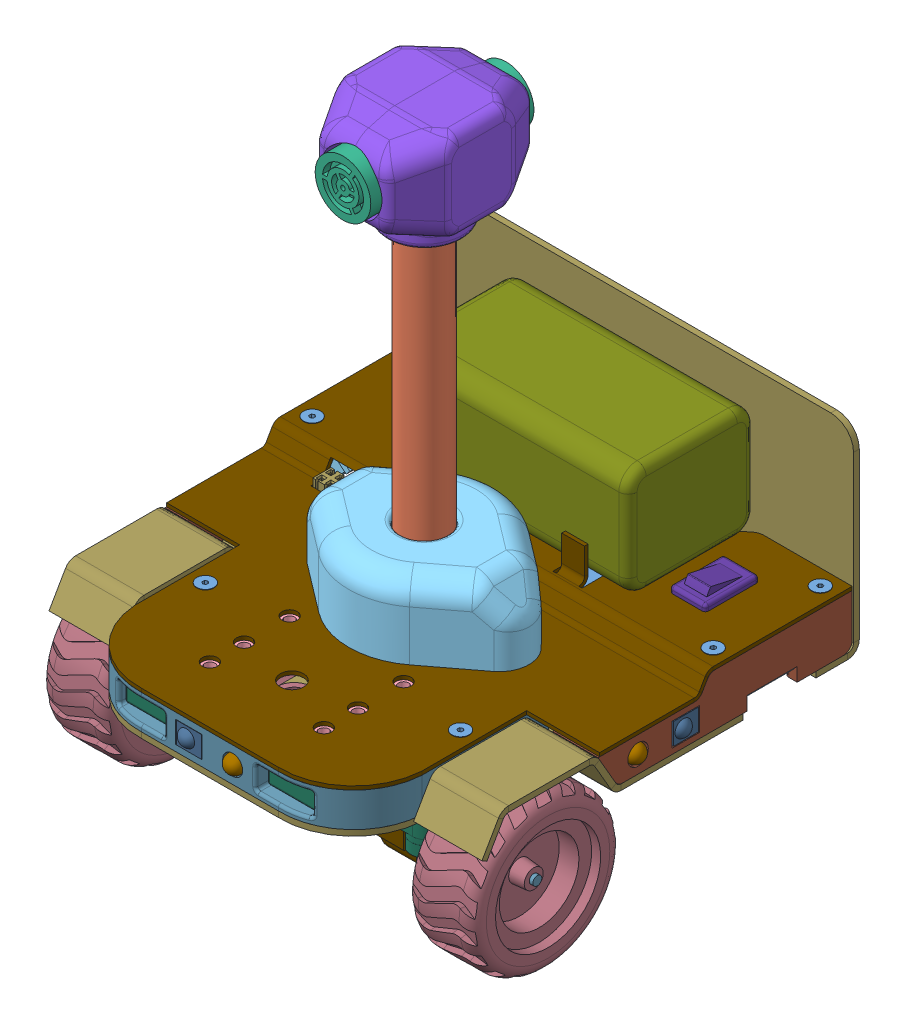
SolidWorks assembly SCOUT REAR, TOP ASSY, configuration Default. Lengths in mm.
Overall size (123.75 170.86 128.74).
86 component instances, 37 part files, 147 mates.
Components (placement in the parent):
- Socket Countersunk Head Cap Screw_AI-18: Socket Countersunk Head Cap Screw_AI [SCHCSCREW 0.086-56x0.3125x0.3125-HX-N] at (-15.9502 58.0469 -46.644) x (0 0 -1) z (1 0 0) size (7.94 4.79 4.79)
- Machine Screw Nut Hex_AI-2: Machine Screw Nut Hex_AI [MSHXNUT 0.086-56-D-N] at (-15.9502 58.0469 -52.9051) size (4.78 5.51 1.68)
- Socket Countersunk Head Cap Screw_AI-1: Socket Countersunk Head Cap Screw_AI [SCHCSCREW 0.086-56x0.188x0.188-HX-N] at (-26.2031 27.9504 40.5909) x (0 1 0) z (0 0 1) size (4.78 4.79 4.79)
- Socket Countersunk Head Cap Screw_AI-2: Socket Countersunk Head Cap Screw_AI [SCHCSCREW 0.086-56x0.188x0.188-HX-N] at (-50.3862 27.9504 -42.0212) x (0 1 0) z (0 0 1) size (4.78 4.79 4.79)
- Socket Countersunk Head Cap Screw_AI-3: Socket Countersunk Head Cap Screw_AI [SCHCSCREW 0.086-56x0.188x0.188-HX-N] at (-63.1312 27.9504 12.5888) x (0 1 0) z (0 0 1) size (4.78 4.79 4.79)
- Socket Countersunk Head Cap Screw_AI-4: Socket Countersunk Head Cap Screw_AI [SCHCSCREW 0.086-56x0.188x0.188-HX-N] at (-33.8762 27.9504 -26.7812) x (0 1 0) z (0 0 1) size (4.78 4.79 4.79)
- Socket Countersunk Head Cap Screw_AI-5: Socket Countersunk Head Cap Screw_AI [SCHCSCREW 0.086-56x0.188x0.188-HX-N] at (-33.8762 27.9504 -42.0212) x (0 1 0) z (0 0 1) size (4.78 4.79 4.79)
- Socket Countersunk Head Cap Screw_AI-6: Socket Countersunk Head Cap Screw_AI [SCHCSCREW 0.086-56x0.188x0.188-HX-N] at (-50.3862 27.9504 -26.7812) x (0 1 0) z (0 0 1) size (4.78 4.79 4.79)
- Socket Countersunk Head Cap Screw_AI-7: Socket Countersunk Head Cap Screw_AI [SCHCSCREW 0.086-56x0.188x0.188-HX-N] at (-21.1312 27.9504 12.5888) x (0 1 0) z (0 0 1) size (4.78 4.79 4.79)
- Socket Countersunk Head Cap Screw_AI-8: Socket Countersunk Head Cap Screw_AI [SCHCSCREW 0.086-56x0.188x0.188-HX-N] at (-26.2031 27.9504 51.7034) x (0 1 0) z (0 0 1) size (4.78 4.79 4.79)
- Socket Countersunk Head Cap Screw_AI-9: Socket Countersunk Head Cap Screw_AI [SCHCSCREW 0.086-56x0.188x0.188-HX-N] at (-58.0593 27.9504 51.7034) x (0 1 0) z (0 0 1) size (4.78 4.79 4.79)
- Socket Countersunk Head Cap Screw_AI-10: Socket Countersunk Head Cap Screw_AI [SCHCSCREW 0.086-56x0.188x0.188-HX-N] at (-58.0593 27.9504 40.5909) x (0 1 0) z (0 0 1) size (4.78 4.79 4.79)
- Socket Countersunk Head Cap Screw_AI-11: Socket Countersunk Head Cap Screw_AI [SCHCSCREW 0.086-56x0.188x0.188-HX-N] at (-75.9169 27.9504 58.6263) x (0 1 0) z (0 0 1) size (4.78 4.79 4.79)
- Socket Countersunk Head Cap Screw_AI-12: Socket Countersunk Head Cap Screw_AI [SCHCSCREW 0.086-56x0.188x0.188-HX-N] at (-8.3456 27.9504 58.6263) x (0 1 0) z (0 0 1) size (4.78 4.79 4.79)
- Socket Countersunk Head Cap Screw_AI-14: Socket Countersunk Head Cap Screw_AI [SCHCSCREW 0.086-56x0.188x0.188-HX-N] at (13.4313 27.9504 6.8738) x (0 1 0) z (0 0 1) size (4.78 4.79 4.79)
- Socket Countersunk Head Cap Screw_AI-15: Socket Countersunk Head Cap Screw_AI [SCHCSCREW 0.086-56x0.188x0.188-HX-N] at (-97.6937 27.9504 6.8738) x (0 1 0) z (0 0 1) size (4.78 4.79 4.79)
- Socket Countersunk Head Cap Screw_AI-16: Socket Countersunk Head Cap Screw_AI [SCHCSCREW 0.086-56x0.188x0.188-HX-N] at (-29.3042 27.9504 -16.291) x (0 1 0) z (0 0 1) size (4.78 4.79 4.79)
- Socket Countersunk Head Cap Screw_AI-17: Socket Countersunk Head Cap Screw_AI [SCHCSCREW 0.086-56x0.188x0.188-HX-N] at (-59.2762 27.9504 -6.766) x (0 1 0) z (0 0 1) size (4.78 4.79 4.79)
- Flat Head 100 Screw_AI-10: Flat Head 100 Screw_AI [CR-FHM1 0.112-40x0.25x0.25-N] at (-63.1312 46.6776 12.5888) x (0 -1 0) z (0 0 1) size (6.35 4.85 4.85)
- Flat Head 100 Screw_AI-11: Flat Head 100 Screw_AI [CR-FHM1 0.112-40x0.25x0.25-N] at (-21.1312 46.6776 12.5888) x (0 -1 0) z (0 0 1) size (6.35 4.85 4.85)
- Socket Head Cap Screw_AI-17: Socket Head Cap Screw_AI [HX-SHCS 0.086-56x0.4375x0.4375-N] at (-77.6912 31.862 47.5138) x (0 -1 0) z (-0.381305 0 -0.924449) size (13.3 3.56 3.56)
- Socket Head Cap Screw_AI-18: Socket Head Cap Screw_AI [HX-SHCS 0.086-56x0.4375x0.4375-N] at (-77.6912 31.862 29.5138) x (0 -1 0) z (0 0 1) size (13.3 3.56 3.56)
- Socket Head Cap Screw_AI-19: Socket Head Cap Screw_AI [HX-SHCS 0.086-56x0.4375x0.4375-N] at (-6.5712 31.862 29.5138) x (0 -1 0) z (0 0 1) size (13.3 3.56 3.56)
- Socket Head Cap Screw_AI-20: Socket Head Cap Screw_AI [HX-SHCS 0.086-56x0.4375x0.4375-N] at (-6.5712 31.862 47.5138) x (0 -1 0) z (0 0 1) size (13.3 3.56 3.56)
- SENSOR, CLIFF, GP2Y0D810-1: SENSOR, CLIFF, GP2Y0D810 [Default] at (9.9271 36.5946 -23.9419) x (0 0 -1) z (0.766044 0.642788 0) size (21.46 9.46 8.89)
- SENSOR, CLIFF, GP2Y0D810-2: SENSOR, CLIFF, GP2Y0D810 [Default] at (-94.1896 36.5946 -23.9419) x (0 0 -1) z (0.766044 -0.642788 0) size (21.46 9.46 8.89)
- SENSOR, SONAR, Maxbotix EZ4-1: SENSOR, SONAR, Maxbotix EZ4 [Default] at (-42.0042 152.0321 6.2388) x (0 1 0) z (0 0 -1) size (19.94 22.1 16.38)
- SENSOR, SONAR, Maxbotix EZ4-2: SENSOR, SONAR, Maxbotix EZ4 [Default] at (-42.0042 152.0321 18.9388) x (0 -1 0) z (0 0 1) size (19.94 22.1 16.38)
- SENSOR, SONAR, MOUNTING BLOCK-1: SENSOR, SONAR, MOUNTING BLOCK [Default] at (-42.1312 151.9686 12.5888) x (-1 0 0) z (0 0 -1) size (22.35 20.07 12.7)
- SENSOR, SONAR, COVER-1: SENSOR, SONAR, COVER [Default] at (-42.0042 152.0321 12.5888) size (15.88 31.75 40.64)
- SENSOR, SONAR, COVER-2: SENSOR, SONAR, COVER [Default] at (-42.0042 152.0321 12.5888) x (-1 0 0) z (0 0 -1) size (15.88 31.75 40.64)
- SENSOR, BOM,TSAL6200-1: SENSOR, BOM,TSAL6200 [Default] at (17.3005 34.4401 13.2873) x (0 0.430029 -0.902815) z (1 0 0) size (5.39 5.8 14.08)
- SENSOR, BOM,TSAL6200-2: SENSOR, BOM,TSAL6200 [Default] at (-101.3647 34.4401 13.2873) x (0 -0.574817 0.818282) z (-1 0 0) size (5.39 5.8 14.08)
- SENSOR, BOM, VISHAY TSOP4838-1: SENSOR, BOM, VISHAY TSOP4838 [Default] at (-100.5062 34.4401 -0.0477) x (0 0 1) z (-1 0 0) size (9.49 6 5.4)
- SENSOR, BOM, VISHAY TSOP4838-2: SENSOR, BOM, VISHAY TSOP4838 [Default] at (16.2438 34.4401 -0.0477) x (0 0 1) z (1 0 0) size (9.49 6 5.4)
- SENSOR, BOM, SIDE MOUNTING BLOCK-3: SENSOR, BOM, SIDE MOUNTING BLOCK [Default] at (-96.1062 29.6776 -46.4027) x (-1 0 0) z (0 0 -1) size (6.35 14.47 70.84)
- SENSOR, BOM, SIDE MOUNTING BLOCK-6: SENSOR, BOM, SIDE MOUNTING BLOCK [right side] at (11.8438 29.6776 -46.4027) x (-1 0 0) z (0 0 -1) size (12.7 14.47 70.84)
- CHASSIS, PLATE, REAR-1: CHASSIS, PLATE, REAR [Default] at (-42.1312 28.0774 12.7174) size (120.65 55.58 120.66)
- ACTUATORS, DRIVETRAIN, TOP ASSY-1: ACTUATORS, DRIVETRAIN, TOP ASSY [Default] at (1.1438 22.1921 32.9919) x (0 0 -1) z (1 0 0) size (42.55 42.54 38.87)
  - ACTUATORS, Pololu Wheel, 49x19-1: ACTUATORS, Pololu Wheel, 49x19 [Default] at (-5.5219 -7.0522 7.705) size (42.55 42.54 19)
  - ACTUATORS, 298-1 Motor-1: ACTUATORS, 298-1 Motor [Default] at (-5.5219 -7.0522 -19.665) x (0 0 -1) z (0 1 0) size (35.87 12 10)
  - ACTUATORS, Pololu Extended Micro Metal Bracket-1: ACTUATORS, Pololu Extended Micro Metal Bracket [Default] at (-5.5219 -2.0522 -11.965) x (-1 0 0) z (0 0 1) size (26.6 19.44 26.04)
- ACTUATORS, DRIVETRAIN, TOP ASSY-2: ACTUATORS, DRIVETRAIN, TOP ASSY [Default] at (-85.4063 22.1921 44.0356) x (0 0 1) z (-1 0 0) size (42.55 42.54 38.87)
  - ACTUATORS, Pololu Wheel, 49x19-1: ACTUATORS, Pololu Wheel, 49x19 [Default] at (-5.5219 -7.0522 7.705) size (42.55 42.54 19)
  - ACTUATORS, 298-1 Motor-1: ACTUATORS, 298-1 Motor [Default] at (-5.5219 -7.0522 -19.665) x (0 0 -1) z (0 1 0) size (35.87 12 10)
  - ACTUATORS, Pololu Extended Micro Metal Bracket-1: ACTUATORS, Pololu Extended Micro Metal Bracket [Default] at (-5.5219 -2.0522 -11.965) x (-1 0 0) z (0 0 1) size (26.6 19.44 26.04)
- CHASSIS, PIVOT, BLOCK-1: CHASSIS, PIVOT, BLOCK [Default] at (-42.1312 36.0276 -35.6712) x (-1 0 0) z (0 0 -1) size (25.4 12.7 25.4)
- ACTUATORS, STEPPER PF35T-48-1: ACTUATORS, STEPPER PF35T-48 [Default] at (-42.1312 31.6776 12.5888) x (-1 0 0) z (0 0 -1) size (50 29.2 35)
- CHASSIS, PLATE, REAR COVER-1: CHASSIS, PLATE, REAR COVER [Default] at (-42.1312 39.2026 72.2788) size (120.65 14.86 118.69)
- ACUATORS, STEPPER, SHAFT, SONAR MOUNT-1: ACUATORS, STEPPER, SHAFT, SONAR MOUNT [Default] at (-42.1312 52.5276 12.5888) x (-0.538443 0 0.842662) z (-0.842662 0 -0.538443) size (6.35 102.11 6.35)
- ACUATORS, STEPPER, SHAFT, SONAR-1: ACUATORS, STEPPER, SHAFT, SONAR [Default] at (-42.1312 46.6776 12.5888) x (-0.849235 0 0.528015) z (-0.528015 0 -0.849235) size (12.7 95.79 12.7)
- ACTUATORS, STEPPER, THREADED STANDOFF-1: ACTUATORS, STEPPER, THREADED STANDOFF [Default] at (-63.1312 30.0026 12.5888) x (-0.08784 0 -0.996135) z (0.996135 0 -0.08784) size (4.76 15.88 4.76)
- ACTUATORS, STEPPER, THREADED STANDOFF-2: ACTUATORS, STEPPER, THREADED STANDOFF [Default] at (-21.1312 30.0026 12.5888) x (0.987866 0 -0.155311) z (0.155311 0 0.987866) size (4.76 15.88 4.76)
- CHASSIS, MOUNTING BLOCK, ACESSORIES-1: CHASSIS, MOUNTING BLOCK, ACESSORIES [Default] at (-58.0062 34.4401 31.0038) size (9.53 9.53 28.57)
- CHASSIS, MOUNTING BLOCK, ACESSORIES-2: CHASSIS, MOUNTING BLOCK, ACESSORIES [Default] at (-26.2562 34.4401 31.0038) x (-1 0 0) z (0 0 1) size (9.53 9.53 28.57)
- ACTUATORS, STEPPER, COVER-1: ACTUATORS, STEPPER, COVER [Default] at (-42.1312 40.2186 12.5888) size (58.51 20.32 41.91)
- PCB, BREAKFLY, TOP ASSY-1: PCB, BREAKFLY, TOP ASSY [Default] at (-76.6011 30.844 -36.6789) size (69.22 11.68 31.75)
  - PCB, Breakfly-1: PCB, Breakfly [Default] at (-10.6151 1.3736 5.7828) size (69.22 1.65 31.75)
  - CONNECTOR, FFC 545482071-1: CONNECTOR, FFC 545482071 [Default] at (-2.3182 2.9996 10.7465) x (-1 0 0) z (0 0 -1) size (15.21 1.2 5)
  - CONNECTOR, JST B3B-ZR-SM4-1: CONNECTOR, JST B3B-ZR-SM4 [Default] at (46.2476 3.0246 30.3118) size (7.5 5 5.2)
  - CONNECTOR, JST B3B-ZR-SM4-2: CONNECTOR, JST B3B-ZR-SM4 [Default] at (23.8988 3.0246 15.228) x (-1 0 0) z (0 0 -1) size (7.5 5 5.2)
  - CONNECTOR, JST B4B-ZR-SM4-1: CONNECTOR, JST B4B-ZR-SM4 [Default] at (58.3639 3.0246 23.0656) x (0 0 -1) z (1 0 0) size (9 5 5.2)
  - CONNECTOR, JST B4B-ZR-SM4-2: CONNECTOR, JST B4B-ZR-SM4 [Default] at (58.3639 3.0246 11.2841) x (0 0 -1) z (1 0 0) size (9 5 5.2)
  - CONNECTOR, JST B5B-ZR-SM4-1: CONNECTOR, JST B5B-ZR-SM4 [Default] at (31.5533 3.0246 30.3118) size (10.5 5 5.2)
  - CONNECTOR, JST B4B-ZR-SM4-3: CONNECTOR, JST B4B-ZR-SM4 [Default] at (12.6237 3.0246 6.3925) x (-1 0 0) z (0 0 -1) size (9 5 5.2)
  - CONNECTOR, JST S6B-ZR-SM4A-1: CONNECTOR, JST S6B-ZR-SM4A [Default] at (4.7961 3.0246 30.4147) x (0 0 -1) z (1 0 0) size (12 3.7 6.5)
  - CONNECTOR, MOLEX 015445810-1: CONNECTOR, MOLEX 015445810 [Default] at (-3.2359 2.6436 33.7255) x (1 0 0) z (0 1 0) size (12.67 5.05 11.68)
- CHASSIS, BUSHING, MMC, 3746K3-1: CHASSIS, BUSHING, MMC, 3746K3 [Default] at (-42.1312 26.4899 48.7838) x (0 1 0) z (0 0 1) size (9.53 12.7 12.7)
- BUMPER, TOP ASSY-1: BUMPER, TOP ASSY [Default] at (-69.0401 23.7228 63.3826) x (-1 0 0) z (0 0 -1) size (80.01 9.52 56.17)
  - BUMPER, REAR-1: BUMPER, REAR [Default] at (-26.9089 5.9548 10.1539) size (80.01 9.53 54.3)
  - SENSOR, BOM, VISHAY TSOP4838-1: SENSOR, BOM, VISHAY TSOP4838 [Default] at (-21.0669 10.6693 -6.9461) x (1 0 0) z (0 0 -1) size (9.49 6 5.4)
  - SENSOR, BOM,TSAL6200-1: SENSOR, BOM,TSAL6200 [Default] at (-33.2589 10.7173 -8.2861) x (-0.636059 -0.771641 0) z (0 0 -1) size (5.39 5.8 14.08)
  - BUMPER, COPPER CONTACT-1: BUMPER, COPPER CONTACT [Default] at (-7.0652 10.7173 -3.1811) x (-1 0 0) z (0 0 -1) size (14.22 6.35 2.54)
  - BUMPER, COPPER CONTACT-2: BUMPER, COPPER CONTACT [Default] at (-46.7527 10.7173 -3.1811) x (-1 0 0) z (0 0 -1) size (14.22 6.35 2.54)
- BATTERY, 3000mAh 7.4V LiIon Pack-1: BATTERY, 3000mAh 7.4V LiIon Pack [Default] at (-42.1312 60.4079 -28.991) x (0 0 1) z (-1 0 0) size (35.56 30.48 66.04)
- BATTERY, SWITCH, CH865-ND-1: BATTERY, SWITCH, CH865-ND [Default] at (-0.8562 45.1679 -27.0248) size (10 15.72 15.01)
- Socket Countersunk Head Cap Screw_AI-19: Socket Countersunk Head Cap Screw_AI [SCHCSCREW 0.086-56x0.188x0.188-HX-N] at (-98.0112 45.2949 -41.9577) x (0 -1 0) z (-0.996542 0 -0.083088) size (4.78 4.79 4.79)
- Socket Countersunk Head Cap Screw_AI-20: Socket Countersunk Head Cap Screw_AI [SCHCSCREW 0.086-56x0.188x0.188-HX-N] at (-98.0112 45.2949 -12.0919) x (0 -1 0) z (-0.546944 0 0.837169) size (4.78 4.79 4.79)
- Socket Countersunk Head Cap Screw_AI-21: Socket Countersunk Head Cap Screw_AI [SCHCSCREW 0.086-56x0.188x0.188-HX-N] at (-77.6912 40.3456 37.9888) x (0 -1 0) z (-0.546944 0 0.837169) size (4.78 4.79 4.79)
- Socket Countersunk Head Cap Screw_AI-23: Socket Countersunk Head Cap Screw_AI [SCHCSCREW 0.086-56x0.188x0.188-HX-N] at (-6.5712 40.3456 37.9888) x (0 -1 0) z (-0.546944 0 0.837169) size (4.78 4.79 4.79)
- Socket Countersunk Head Cap Screw_AI-24: Socket Countersunk Head Cap Screw_AI [SCHCSCREW 0.086-56x0.188x0.188-HX-N] at (13.7488 45.2949 -12.0919) x (0 -1 0) z (-0.814522 0 0.580132) size (4.78 4.79 4.79)
- Socket Countersunk Head Cap Screw_AI-25: Socket Countersunk Head Cap Screw_AI [SCHCSCREW 0.086-56x0.188x0.188-HX-N] at (13.7488 45.2949 -41.9577) x (0 -1 0) z (0.724583 0 0.689187) size (4.78 4.79 4.79)
- Machine Screw Nut Hex_AI-3: Machine Screw Nut Hex_AI [MSHXNUT 0.086-56-D-N] at (-15.9502 58.0469 -48.3712) size (4.78 5.51 1.68)
- ACTUATORS, DRIVETRAIN, COVER-1: ACTUATORS, DRIVETRAIN, COVER [Default] at (-73.4412 28.0774 37.4958) size (17.91 19.44 26.6)
- ACTUATORS, DRIVETRAIN, COVER-2: ACTUATORS, DRIVETRAIN, COVER [Default] at (-10.8212 28.0774 39.5318) x (-1 0 0) z (0 0 -1) size (17.91 19.44 26.6)
- CHASSIS, SHEET, BREAKFLY COVER-1: CHASSIS, SHEET, BREAKFLY COVER [Default] at (-42.1312 43.755 -26.0094) size (63.5 2.6 20.66)
Mates (geometry in assembly coordinates):
- Coincident1: coincident aligned: plane of ACTUATORS, DRIVETRAIN, TOP ASSY-1/ACTUATORS, Pololu Extended Micro Metal Bracket-1 through (6.4788 20.1399 25.2138) normal (0 1 0); plane of ACTUATORS, DRIVETRAIN, TOP ASSY-2/ACTUATORS, Pololu Extended Micro Metal Bracket-1 through (-90.7412 20.1399 51.8138) normal (0 1 0)
- Coincident2: coincident anti-aligned: plane of CHASSIS, PLATE, REAR-1 through (-82.1362 28.0774 18.9388) normal (0 -1 0); plane of ACTUATORS, DRIVETRAIN, TOP ASSY-2/ACTUATORS, Pololu Extended Micro Metal Bracket-1 through (-66.7356 28.0774 51.8138) normal (0 1 0)
- Coincident3: coincident aligned: plane of Socket Head Cap Screw_AI-17 through (-77.6912 31.862 47.5138) normal (0 1 0); plane of Socket Head Cap Screw_AI-18 through (-77.6912 31.862 29.5138) normal (0 1 0)
- Coincident4: coincident aligned: plane of Socket Head Cap Screw_AI-19 through (-6.5712 31.862 29.5138) normal (0 1 0); plane of Socket Head Cap Screw_AI-20 through (-6.5712 31.862 47.5138) normal (0 1 0)
- Coincident5: coincident aligned: plane of Socket Head Cap Screw_AI-18 through (-77.6912 31.862 29.5138) normal (0 1 0); plane of Socket Head Cap Screw_AI-19 through (-6.5712 31.862 29.5138) normal (0 1 0)
- Coincident6: coincident anti-aligned: plane of CHASSIS, PLATE, REAR-1 through (-82.1362 29.6776 18.9388) normal (0 1 0); plane of Socket Head Cap Screw_AI-19 through (-4.7932 29.6776 29.5138) normal (0 -1 0)
- Concentric6: concentric aligned: cylinder of CHASSIS, PLATE, REAR-1 through (-77.6912 29.6776 29.5138) axis (0 1 0) radius 1.2192; cylinder of Socket Head Cap Screw_AI-18 through (-77.6912 63.612 29.5138) axis (0 1 0) radius 1.0922
- Concentric7: concentric aligned: cylinder of CHASSIS, PLATE, REAR-1 through (-77.6912 29.6776 47.5138) axis (0 1 0) radius 1.2192; cylinder of Socket Head Cap Screw_AI-17 through (-77.6912 63.612 47.5138) axis (0 1 0) radius 1.0922
- Concentric8: concentric aligned: cylinder of CHASSIS, PLATE, REAR-1 through (-6.5712 29.6776 29.5138) axis (0 1 0) radius 1.2192; cylinder of Socket Head Cap Screw_AI-19 through (-6.5712 63.612 29.5138) axis (0 1 0) radius 1.0922
- Concentric9: concentric aligned: cylinder of CHASSIS, PLATE, REAR-1 through (-6.5712 29.6776 47.5138) axis (0 1 0) radius 1.2192; cylinder of Socket Head Cap Screw_AI-20 through (-6.5712 63.612 47.5138) axis (0 1 0) radius 1.0922
- Concentric40: concentric aligned: cylinder of ACTUATORS, DRIVETRAIN, TOP ASSY-2/ACTUATORS, Pololu Extended Micro Metal Bracket-1 through (-77.6912 20.1399 29.5138) axis (0 1 0) radius 1.2192; cylinder of Socket Head Cap Screw_AI-18 through (-77.6912 63.612 29.5138) axis (0 1 0) radius 1.0922
- Concentric41: concentric aligned: cylinder of ACTUATORS, DRIVETRAIN, TOP ASSY-2/ACTUATORS, Pololu Extended Micro Metal Bracket-1 through (-77.6912 20.1399 47.5138) axis (0 1 0) radius 1.2192; cylinder of Socket Head Cap Screw_AI-17 through (-77.6912 63.612 47.5138) axis (0 1 0) radius 1.0922
- Concentric42: concentric aligned: cylinder of ACTUATORS, DRIVETRAIN, TOP ASSY-1/ACTUATORS, Pololu Extended Micro Metal Bracket-1 through (-6.5712 20.1399 29.5138) axis (0 1 0) radius 1.2192; cylinder of Socket Head Cap Screw_AI-19 through (-6.5712 63.612 29.5138) axis (0 1 0) radius 1.0922
- Concentric43: concentric aligned: cylinder of ACTUATORS, DRIVETRAIN, TOP ASSY-1/ACTUATORS, Pololu Extended Micro Metal Bracket-1 through (-6.5712 20.1399 47.5138) axis (0 1 0) radius 1.2192; cylinder of Socket Head Cap Screw_AI-20 through (-6.5712 63.612 47.5138) axis (0 1 0) radius 1.0922
- Concentric44: concentric aligned: cylinder of CHASSIS, PLATE, REAR-1 through (-95.2182 35.3687 -33.4034) axis (0.642788 0.766044 0) radius 1.0287; cylinder of SENSOR, CLIFF, GP2Y0D810-2 through (-99.2509 30.5627 -33.4034) axis (0.642788 0.766044 0) radius 1.0287
- Parallel1: parallel anti-aligned: plane of CHASSIS, PLATE, REAR-1 through (-97.6765 37.4315 -30.9045) normal (0 0 1); plane of SENSOR, CLIFF, GP2Y0D810-2 through (-89.7641 34.9535 -35.8291) normal (0 0 -1)
- Coincident93: coincident anti-aligned: plane of CHASSIS, PLATE, REAR-1 through (1.6838 29.6776 -30.9045) normal (-0.642788 0.766044 0); plane of SENSOR, CLIFF, GP2Y0D810-1 through (6.522 33.7374 -35.8291) normal (0.642788 -0.766044 0)
- Concentric45: concentric aligned: cylinder of CHASSIS, PLATE, REAR-1 through (10.9557 35.3687 -33.4034) axis (-0.642788 0.766044 0) radius 1.0287; cylinder of SENSOR, CLIFF, GP2Y0D810-1 through (14.9884 30.5627 -33.4034) axis (-0.642788 0.766044 0) radius 1.0287
- Parallel2: parallel aligned: plane of SENSOR, CLIFF, GP2Y0D810-1 through (12.3118 40.6679 -14.3661) normal (0.766044 0.642788 0); plane of CHASSIS, PLATE, REAR-1 through (13.414 37.4315 -35.9845) normal (0.766044 0.642788 0)
- Coincident103: coincident anti-aligned: plane of CHASSIS, PLATE, REAR-1 through (-82.1362 29.6776 18.9388) normal (0 1 0); plane of CHASSIS, PIVOT, BLOCK-1 through (-29.4312 29.6776 -48.3712) normal (0 -1 0)
- Concentric46: concentric aligned: cylinder of CHASSIS, PLATE, REAR-1 through (-33.8762 28.0774 -42.0212) axis (0 -1 0) radius 1.632; cylinder of CHASSIS, PIVOT, BLOCK-1 through (-33.8762 29.6776 -42.0212) axis (0 -1 0) radius 1.4224
- Concentric54: concentric aligned: cylinder of CHASSIS, PLATE, REAR-1 through (-50.3862 28.0774 -26.7812) axis (0 -1 0) radius 1.632; cylinder of CHASSIS, PIVOT, BLOCK-1 through (-50.3862 29.6776 -26.7812) axis (0 -1 0) radius 1.4224
- Coincident104: coincident anti-aligned: plane of CHASSIS, PLATE, REAR-1 through (-82.1362 29.6776 18.9388) normal (0 1 0); plane of ACTUATORS, STEPPER PF35T-48-1 through (-42.1312 29.6776 12.5888) normal (0 -1 0)
- Coincident117: coincident aligned: plane of SENSOR, SONAR, Maxbotix EZ4-1 through (-53.0532 162.0016 4.6513) normal (0 1 0); plane of SENSOR, SONAR, Maxbotix EZ4-2 through (-53.0532 162.0016 20.5263) normal (0 1 0)
- Coincident125: coincident anti-aligned: plane of SENSOR, SONAR, Maxbotix EZ4-1 through (-30.9552 162.0016 6.2388) normal (0 0 1); plane of SENSOR, SONAR, MOUNTING BLOCK-1 through (-53.3072 162.0016 6.2388) normal (0 0 -1)
- Concentric64: concentric aligned: cylinder of ACTUATORS, STEPPER PF35T-48-1 through (-42.1312 58.8776 12.5888) axis (0 -1 0) radius 1; cylinder of SENSOR, SONAR, MOUNTING BLOCK-1 through (-42.1312 154.6356 12.5888) axis (0 -1 0) radius 2.3813
- Coincident129: coincident anti-aligned: plane of ACTUATORS, STEPPER PF35T-48-1 through (-42.1312 58.8776 12.5888) normal (0 1 0); plane of ACUATORS, STEPPER, SHAFT, SONAR MOUNT-1 through (-42.1312 58.8776 12.5888) normal (0 -1 0)
- Concentric65: concentric aligned: cylinder of ACTUATORS, STEPPER PF35T-48-1 through (-42.1312 58.8776 12.5888) axis (0 -1 0) radius 1; cylinder of ACUATORS, STEPPER, SHAFT, SONAR MOUNT-1 through (-42.1312 154.6356 12.5888) axis (0 -1 0) radius 3.175
- Concentric66: concentric aligned: cylinder of ACUATORS, STEPPER, SHAFT, SONAR MOUNT-1 through (-42.1312 154.6356 12.5888) axis (0 -1 0) radius 3.175; cylinder of ACUATORS, STEPPER, SHAFT, SONAR-1 through (-42.1312 141.9276 12.5888) axis (0 -1 0) radius 5.5563
- Coincident131: coincident anti-aligned: plane of ACTUATORS, STEPPER PF35T-48-1 through (-21.1312 45.8776 12.5888) normal (0 -1 0); plane of ACTUATORS, STEPPER, THREADED STANDOFF-1 through (-63.1312 45.8776 12.5888) normal (0 1 0)
- Coincident132: coincident anti-aligned: plane of ACTUATORS, STEPPER PF35T-48-1 through (-21.1312 45.8776 12.5888) normal (0 -1 0); plane of ACTUATORS, STEPPER, THREADED STANDOFF-2 through (-21.1312 45.8776 12.5888) normal (0 1 0)
- Coincident133: coincident aligned: plane of Flat Head 100 Screw_AI-10 through (-61.7088 40.3276 12.5888) normal (0 -1 0); plane of Flat Head 100 Screw_AI-11 through (-19.7088 40.3276 12.5888) normal (0 -1 0)
- Concentric69: concentric anti-aligned: cylinder of ACTUATORS, STEPPER, THREADED STANDOFF-2 through (-21.1312 45.8776 12.5888) axis (0 -1 0) radius 2.3813; cylinder of Flat Head 100 Screw_AI-11 through (-21.1312 53.0276 12.5888) axis (0 1 0) radius 1.4224
- Concentric70: concentric anti-aligned: cylinder of ACTUATORS, STEPPER, THREADED STANDOFF-1 through (-63.1312 45.8776 12.5888) axis (0 -1 0) radius 2.3813; cylinder of Flat Head 100 Screw_AI-10 through (-63.1312 53.0276 12.5888) axis (0 1 0) radius 1.4224
- Coincident134: coincident aligned: plane of ACTUATORS, STEPPER PF35T-48-1 through (-21.1312 46.6776 12.5888) normal (0 1 0); plane of Flat Head 100 Screw_AI-10 through (-63.1312 46.6776 12.5888) normal (0 1 0)
- Coincident137: coincident anti-aligned: plane of SENSOR, SONAR, MOUNTING BLOCK-1 through (-42.1312 154.6356 12.5888) normal (0 -1 0); plane of ACUATORS, STEPPER, SHAFT, SONAR MOUNT-1 through (-42.1312 154.6356 12.5888) normal (0 1 0)
- Coincident139: coincident aligned: plane of CHASSIS, MOUNTING BLOCK, ACESSORIES-1 through (-53.2437 39.2026 31.0038) normal (0 0 -1); plane of CHASSIS, MOUNTING BLOCK, ACESSORIES-2 through (-31.0187 29.6776 31.0038) normal (0 0 -1)
- Coincident140: coincident anti-aligned: plane of CHASSIS, PLATE, REAR-1 through (-82.1362 29.6776 18.9388) normal (0 1 0); plane of CHASSIS, MOUNTING BLOCK, ACESSORIES-1 through (-62.7687 29.6776 59.5788) normal (0 -1 0)
- Concentric75: concentric aligned: cylinder of CHASSIS, PLATE, REAR COVER-1 through (-58.0062 40.2186 34.1788) axis (0 1 0) radius 2.1082; cylinder of CHASSIS, MOUNTING BLOCK, ACESSORIES-1 through (-58.0062 39.2026 34.1788) axis (0 1 0) radius 1.4224
- Coincident144: coincident anti-aligned: plane of SENSOR, SONAR, Maxbotix EZ4-2 through (-30.9552 142.0626 18.9388) normal (0 0 -1); plane of SENSOR, SONAR, MOUNTING BLOCK-1 through (-53.3072 162.0016 18.9388) normal (0 0 1)
- Coincident149: coincident anti-aligned: plane of CHASSIS, PLATE, REAR-1 through (-85.9462 29.6776 -30.9045) normal (0.642788 0.766044 0); plane of SENSOR, CLIFF, GP2Y0D810-2 through (-97.5946 39.4518 -35.8291) normal (-0.642788 -0.766044 0)
- Concentric81: concentric aligned: cylinder of ACTUATORS, STEPPER PF35T-48-1 through (-63.1312 46.6776 12.5888) axis (0 -1 0) radius 2.413; cylinder of ACTUATORS, STEPPER, THREADED STANDOFF-1 through (-63.1312 45.8776 12.5888) axis (0 -1 0) radius 2.3813
- Concentric82: concentric aligned: cylinder of SENSOR, SONAR, Maxbotix EZ4-2 through (-42.0042 152.0321 35.3218) axis (0 0 -1) radius 7.747; cylinder of SENSOR, SONAR, COVER-1 through (-42.0042 152.0321 32.9088) axis (0 0 -1) radius 8.382
- Concentric83: concentric anti-aligned: cylinder of SENSOR, SONAR, COVER-1 through (-51.5292 162.0016 1.4763) axis (1 0 0) radius 0.889; cylinder of SENSOR, SONAR, COVER-2 through (-32.4792 162.0016 1.4763) axis (-1 0 0) radius 0.889
- Concentric84: concentric anti-aligned: cylinder of SENSOR, SONAR, Maxbotix EZ4-2 through (-42.0042 152.0321 35.3218) axis (0 0 -1) radius 7.747; cylinder of SENSOR, SONAR, COVER-2 through (-42.0042 152.0321 -7.7312) axis (0 0 1) radius 8.382
- Coincident153: coincident aligned: plane of SENSOR, SONAR, MOUNTING BLOCK-1 through (-42.1312 151.9686 12.5888) normal (0 0 -1); plane of SENSOR, SONAR, COVER-2 through (-42.0042 152.0321 12.5888) normal (0 0 -1)
- Parallel3: parallel aligned: plane of SENSOR, SONAR, MOUNTING BLOCK-1; plane of SENSOR, SONAR, COVER-1 through (-42.0042 152.0321 12.5888) normal (0 1 0)
- Concentric89: concentric aligned: cylinder of ACUATORS, STEPPER, SHAFT, SONAR-1 through (-42.1312 141.9276 12.5888) axis (0 -1 0) radius 5.5563; cylinder of ACTUATORS, STEPPER, COVER-1 through (-42.1312 60.5386 12.5888) axis (0 -1 0) radius 6.4135
- Concentric90: concentric aligned: cylinder of ACTUATORS, STEPPER, THREADED STANDOFF-1 through (-63.1312 45.8776 12.5888) axis (0 -1 0) radius 2.3813; cylinder of ACTUATORS, STEPPER, COVER-1 through (-63.1312 60.5386 12.5888) axis (0 -1 0) radius 8.255
- Coincident157: coincident aligned: plane of SENSOR, SONAR, Maxbotix EZ4-1 through (-30.9552 142.0626 4.6513) normal (1 0 0); plane of SENSOR, SONAR, MOUNTING BLOCK-1 through (-30.9552 141.9356 6.2388) normal (1 0 0)
- Coincident158: coincident aligned: plane of SENSOR, SONAR, Maxbotix EZ4-2 through (-53.0532 162.0016 20.5263) normal (0 1 0); plane of SENSOR, SONAR, MOUNTING BLOCK-1 through (-30.9552 162.0016 6.2388) normal (0 1 0)
- Coincident159: coincident aligned: plane of SENSOR, SONAR, Maxbotix EZ4-2 through (-30.9552 162.0016 20.5263) normal (1 0 0); plane of SENSOR, SONAR, MOUNTING BLOCK-1 through (-30.9552 141.9356 6.2388) normal (1 0 0)
- Coincident160: coincident anti-aligned: plane of ACTUATORS, STEPPER PF35T-48-1 through (-21.1312 46.6776 12.5888) normal (0 1 0); plane of ACUATORS, STEPPER, SHAFT, SONAR-1 through (-42.1312 46.6776 12.5888) normal (0 -1 0)
- Distance9: distance = 2.54 mm anti-aligned: plane of CHASSIS, PLATE, REAR-1 through (-82.1362 29.6776 18.9388) normal (0 1 0); plane of PCB, BREAKFLY, TOP ASSY-1/PCB, Breakfly-1 through (-87.2162 32.2176 0.854) normal (0 -1 0)
- Concentric91: concentric anti-aligned: cylinder of CHASSIS, PLATE, REAR-1 through (-42.1312 28.0774 48.7838) axis (0 1 0) radius 4.5212; cylinder of CHASSIS, BUSHING, MMC, 3746K3-1 through (-42.1312 26.4899 48.7838) axis (0 -1 0) radius 4.7625
- Coincident162: coincident anti-aligned: plane of CHASSIS, PLATE, REAR-1 through (-82.1362 28.0774 18.9388) normal (0 -1 0); plane of CHASSIS, BUSHING, MMC, 3746K3-1 through (-48.4812 28.0774 48.7838) normal (0 1 0)
- Coincident171: coincident anti-aligned: plane of CHASSIS, PLATE, REAR-1 through (-82.1362 29.6776 18.9388) normal (0 1 0); plane of BUMPER, TOP ASSY-1/BUMPER, REAR-1 through (-22.4072 29.6776 51.97) normal (0 -1 0)
- Coincident172: coincident aligned: plane of CHASSIS, PLATE, REAR-1 through (-61.1812 28.0774 72.2788) normal (0 0 1); plane of BUMPER, TOP ASSY-1/BUMPER, REAR-1 through (-23.0812 39.2026 72.2788) normal (0 0 1)
- Concentric95: concentric anti-aligned: cylinder of CHASSIS, PLATE, REAR-1 through (-61.8553 28.0774 51.97) axis (0 1 0) radius 20.32; cylinder of BUMPER, TOP ASSY-1/BUMPER, REAR-1 through (-61.8553 39.2026 51.97) axis (0 -1 0) radius 20.32
- Coincident174: coincident aligned: plane of Socket Countersunk Head Cap Screw_AI-7 through (-21.1312 27.9504 12.5888) normal (0 -1 0); plane of Socket Countersunk Head Cap Screw_AI-8 through (-26.2031 27.9504 51.7034) normal (0 -1 0)
- Coincident175: coincident aligned: plane of Socket Countersunk Head Cap Screw_AI-6 through (-50.3862 27.9504 -26.7812) normal (0 -1 0); plane of Socket Countersunk Head Cap Screw_AI-7 through (-21.1312 27.9504 12.5888) normal (0 -1 0)
- Coincident176: coincident aligned: plane of Socket Countersunk Head Cap Screw_AI-2 through (-50.3862 27.9504 -42.0212) normal (0 -1 0); plane of Socket Countersunk Head Cap Screw_AI-6 through (-50.3862 27.9504 -26.7812) normal (0 -1 0)
- Coincident178: coincident aligned: plane of Socket Countersunk Head Cap Screw_AI-1 through (-26.2031 27.9504 40.5909) normal (0 -1 0); plane of Socket Countersunk Head Cap Screw_AI-3 through (-63.1312 27.9504 12.5888) normal (0 -1 0)
- Coincident179: coincident aligned: plane of Socket Countersunk Head Cap Screw_AI-4 through (-33.8762 27.9504 -26.7812) normal (0 -1 0); plane of Socket Countersunk Head Cap Screw_AI-5 through (-33.8762 27.9504 -42.0212) normal (0 -1 0)
- Coincident180: coincident aligned: plane of Socket Countersunk Head Cap Screw_AI-1 through (-26.2031 27.9504 40.5909) normal (0 -1 0); plane of Socket Countersunk Head Cap Screw_AI-4 through (-33.8762 27.9504 -26.7812) normal (0 -1 0)
- Coincident181: coincident aligned: plane of Socket Countersunk Head Cap Screw_AI-1 through (-26.2031 27.9504 40.5909) normal (0 -1 0); plane of Socket Countersunk Head Cap Screw_AI-9 through (-58.0593 27.9504 51.7034) normal (0 -1 0)
- Coincident182: coincident aligned: plane of Socket Countersunk Head Cap Screw_AI-9 through (-58.0593 27.9504 51.7034) normal (0 -1 0); plane of Socket Countersunk Head Cap Screw_AI-10 through (-58.0593 27.9504 40.5909) normal (0 -1 0)
- Coincident183: coincident aligned: plane of Socket Countersunk Head Cap Screw_AI-11 through (-75.9169 27.9504 58.6263) normal (0 -1 0); plane of Socket Countersunk Head Cap Screw_AI-12 through (-8.3456 27.9504 58.6263) normal (0 -1 0)
- Concentric96: concentric anti-aligned: cylinder of CHASSIS, MOUNTING BLOCK, ACESSORIES-2 through (-26.2031 39.2026 51.7034) axis (0 1 0) radius 1.4224; cylinder of Socket Countersunk Head Cap Screw_AI-8 through (-26.2031 27.9504 51.7034) axis (0 -1 0) radius 1.0922
- Concentric97: concentric anti-aligned: cylinder of CHASSIS, MOUNTING BLOCK, ACESSORIES-2 through (-26.2031 39.2026 40.5909) axis (0 1 0) radius 1.4224; cylinder of Socket Countersunk Head Cap Screw_AI-1 through (-26.2031 27.9504 40.5909) axis (0 -1 0) radius 1.0922
- Concentric98: concentric aligned: cylinder of CHASSIS, MOUNTING BLOCK, ACESSORIES-1 through (-58.0593 29.6776 51.7034) axis (0 -1 0) radius 1.4224; cylinder of Socket Countersunk Head Cap Screw_AI-9 through (-58.0593 27.9504 51.7034) axis (0 -1 0) radius 1.0922
- Concentric99: concentric aligned: cylinder of CHASSIS, MOUNTING BLOCK, ACESSORIES-1 through (-58.0593 29.6776 40.5909) axis (0 -1 0) radius 1.4224; cylinder of Socket Countersunk Head Cap Screw_AI-10 through (-58.0593 27.9504 40.5909) axis (0 -1 0) radius 1.0922
- Concentric100: concentric aligned: cylinder of ACTUATORS, STEPPER, THREADED STANDOFF-2 through (-21.1312 30.0026 12.5888) axis (0 -1 0) radius 1.4224; cylinder of Socket Countersunk Head Cap Screw_AI-7 through (-21.1312 27.9504 12.5888) axis (0 -1 0) radius 1.0922
- Concentric101: concentric aligned: cylinder of ACTUATORS, STEPPER, THREADED STANDOFF-1 through (-63.1312 30.0026 12.5888) axis (0 -1 0) radius 1.4224; cylinder of Socket Countersunk Head Cap Screw_AI-3 through (-63.1312 27.9504 12.5888) axis (0 -1 0) radius 1.0922
- Concentric102: concentric aligned: cylinder of CHASSIS, PIVOT, BLOCK-1 through (-33.8762 29.6776 -26.7812) axis (0 -1 0) radius 1.4224; cylinder of Socket Countersunk Head Cap Screw_AI-4 through (-33.8762 27.9504 -26.7812) axis (0 -1 0) radius 1.0922
- Concentric103: concentric aligned: cylinder of CHASSIS, PIVOT, BLOCK-1 through (-50.3862 29.6776 -26.7812) axis (0 -1 0) radius 1.4224; cylinder of Socket Countersunk Head Cap Screw_AI-6 through (-50.3862 27.9504 -26.7812) axis (0 -1 0) radius 1.0922
- Concentric104: concentric aligned: cylinder of CHASSIS, PIVOT, BLOCK-1 through (-33.8762 29.6776 -42.0212) axis (0 -1 0) radius 1.4224; cylinder of Socket Countersunk Head Cap Screw_AI-5 through (-33.8762 27.9504 -42.0212) axis (0 -1 0) radius 1.0922
- Concentric105: concentric aligned: cylinder of CHASSIS, PIVOT, BLOCK-1 through (-50.3862 29.6776 -42.0212) axis (0 -1 0) radius 1.4224; cylinder of Socket Countersunk Head Cap Screw_AI-2 through (-50.3862 27.9504 -42.0212) axis (0 -1 0) radius 1.0922
- Distance10: distance = 0.127 mm aligned: plane of Socket Countersunk Head Cap Screw_AI-7 through (-21.1312 27.9504 12.5888) normal (0 -1 0); plane of CHASSIS, PLATE, REAR-1 through (-82.1362 28.0774 18.9388) normal (0 -1 0)
- Coincident185: coincident aligned: plane of Socket Countersunk Head Cap Screw_AI-11 through (-75.9169 27.9504 58.6263) normal (0 -1 0); plane of Socket Countersunk Head Cap Screw_AI-12 through (-8.3456 27.9504 58.6263) normal (0 -1 0)
- Concentric106: concentric aligned: cylinder of BUMPER, TOP ASSY-1/BUMPER, REAR-1 through (-75.9169 29.6776 58.6263) axis (0 -1 0) radius 1.0922; cylinder of Socket Countersunk Head Cap Screw_AI-11 through (-75.9169 27.9504 58.6263) axis (0 -1 0) radius 1.0922
- Concentric107: concentric aligned: cylinder of BUMPER, TOP ASSY-1/BUMPER, REAR-1 through (-8.3456 29.6776 58.6263) axis (0 -1 0) radius 1.0922; cylinder of Socket Countersunk Head Cap Screw_AI-12 through (-8.3456 27.9504 58.6263) axis (0 -1 0) radius 1.0922
- Coincident186: coincident aligned: plane of Socket Countersunk Head Cap Screw_AI-8 through (-26.2031 27.9504 51.7034) normal (0 -1 0); plane of Socket Countersunk Head Cap Screw_AI-12 through (-8.3456 27.9504 58.6263) normal (0 -1 0)
- Coincident187: coincident aligned: plane of Socket Countersunk Head Cap Screw_AI-14 through (13.4313 27.9504 6.8738) normal (0 -1 0); plane of Socket Countersunk Head Cap Screw_AI-15 through (-97.6937 27.9504 6.8738) normal (0 -1 0)
- Coincident188: coincident aligned: plane of Socket Countersunk Head Cap Screw_AI-3 through (-63.1312 27.9504 12.5888) normal (0 -1 0); plane of Socket Countersunk Head Cap Screw_AI-14 through (13.4313 27.9504 6.8738) normal (0 -1 0)
- Distance11: distance = 15.875 mm anti-aligned: plane of CHASSIS, PLATE, REAR-1 through (18.1938 83.6526 -46.771) normal (0 0 1); plane of PCB, BREAKFLY, TOP ASSY-1/PCB, Breakfly-1 through (-87.2162 33.8686 -30.896) normal (0 0 -1)
- Distance12: distance = 15.24 mm aligned: plane of PCB, BREAKFLY, TOP ASSY-1/PCB, Breakfly-1 through (-87.2162 33.8686 -30.896) normal (-1 0 0); plane of CHASSIS, PLATE, REAR-1 through (-102.4562 29.6776 18.9388) normal (-1 0 0)
- Coincident189: coincident aligned: plane of CHASSIS, MOUNTING BLOCK, ACESSORIES-1 through (-62.7687 39.2026 59.5788) normal (0 1 0); plane of CHASSIS, MOUNTING BLOCK, ACESSORIES-2 through (-21.4937 39.2026 59.5788) normal (0 1 0)
- Coincident190: coincident aligned: plane of Socket Countersunk Head Cap Screw_AI-16 through (-29.3042 27.9504 -16.291) normal (0 -1 0); plane of Socket Countersunk Head Cap Screw_AI-17 through (-59.2762 27.9504 -6.766) normal (0 -1 0)
- Coincident191: coincident aligned: plane of Socket Countersunk Head Cap Screw_AI-14 through (13.4313 27.9504 6.8738) normal (0 -1 0); plane of Socket Countersunk Head Cap Screw_AI-16 through (-29.3042 27.9504 -16.291) normal (0 -1 0)
- Concentric110: concentric anti-aligned: cylinder of CHASSIS, PLATE, REAR-1 through (-29.3042 29.6776 -16.291) axis (0 1 0) radius 1.632; cylinder of Socket Countersunk Head Cap Screw_AI-16 through (-29.3042 27.9504 -16.291) axis (0 -1 0) radius 1.0922
- Concentric111: concentric anti-aligned: cylinder of CHASSIS, PLATE, REAR-1 through (-59.2762 29.6776 -6.766) axis (0 1 0) radius 1.632; cylinder of Socket Countersunk Head Cap Screw_AI-17 through (-59.2762 27.9504 -6.766) axis (0 -1 0) radius 1.0922
- Concentric113: concentric anti-aligned: cylinder of CHASSIS, PLATE, REAR COVER-1 through (-22.4072 40.2186 51.97) axis (0 1 0) radius 20.32; cylinder of BUMPER, TOP ASSY-1/BUMPER, REAR-1 through (-22.4072 39.2026 51.97) axis (0 -1 0) radius 20.32
- Concentric114: concentric anti-aligned: cylinder of CHASSIS, PLATE, REAR COVER-1 through (-26.2562 40.2186 56.4038) axis (0 1 0) radius 2.1082; cylinder of CHASSIS, MOUNTING BLOCK, ACESSORIES-2 through (-26.2562 29.6776 56.4038) axis (0 -1 0) radius 1.4224
- Concentric115: concentric aligned: cylinder of CHASSIS, PLATE, REAR-1 through (-61.8553 28.0774 51.97) axis (0 1 0) radius 20.32; cylinder of CHASSIS, PLATE, REAR COVER-1 through (-61.8553 40.2186 51.97) axis (0 1 0) radius 20.32
- Concentric116: concentric aligned: cylinder of CHASSIS, PLATE, REAR-1 through (-21.1312 28.0774 12.5888) axis (0 -1 0) radius 1.632; cylinder of ACTUATORS, STEPPER, THREADED STANDOFF-2 through (-21.1312 45.8776 12.5888) axis (0 -1 0) radius 2.3813
- Concentric117: concentric aligned: cylinder of ACTUATORS, STEPPER PF35T-48-1 through (-21.1312 46.6776 12.5888) axis (0 -1 0) radius 2.413; cylinder of ACTUATORS, STEPPER, THREADED STANDOFF-2 through (-21.1312 45.8776 12.5888) axis (0 -1 0) radius 2.3813
- Concentric118: concentric anti-aligned: cylinder of ACTUATORS, STEPPER PF35T-48-1 through (-42.1312 45.8776 12.5888) axis (0 -1 0) radius 17.5; cylinder of CHASSIS, PLATE, REAR COVER-1 through (-42.1312 40.2186 12.5888) axis (0 1 0) radius 18.415
- Coincident194: coincident anti-aligned: plane of CHASSIS, PLATE, REAR COVER-1 through (-61.8553 39.2026 51.97) normal (0 -1 0); plane of BUMPER, TOP ASSY-1/BUMPER, REAR-1 through (-22.4072 39.2026 51.97) normal (0 1 0)
- Coincident195: coincident anti-aligned: plane of CHASSIS, PLATE, REAR-1 through (-42.1312 28.0774 12.7174) normal (1 0 0); plane of BATTERY, 3000mAh 7.4V LiIon Pack-1 through (-42.1312 60.4079 -28.991) normal (-1 0 0)
- Coincident196: coincident anti-aligned: plane of CHASSIS, PLATE, REAR COVER-1 through (18.1938 45.1679 -6.7303) normal (0 1 0); plane of BATTERY, 3000mAh 7.4V LiIon Pack-1 through (-75.1512 45.1679 -41.691) normal (0 -1 0)
- Coincident197: coincident anti-aligned: plane of CHASSIS, PLATE, REAR-1 through (18.1938 83.6526 -46.771) normal (0 0 1); plane of BATTERY, 3000mAh 7.4V LiIon Pack-1 through (-75.1512 50.2479 -46.771) normal (0 0 -1)
- Coincident198: coincident anti-aligned: plane of CHASSIS, PLATE, REAR-1 through (-82.1362 29.6776 18.9388) normal (0 1 0); plane of SENSOR, BOM, SIDE MOUNTING BLOCK-3 through (-102.4562 29.6776 17.4723) normal (0 -1 0)
- Coincident199: coincident aligned: plane of CHASSIS, PLATE, REAR COVER-1 through (18.1938 45.1679 -46.4027) normal (0 0 -1); plane of SENSOR, BOM, SIDE MOUNTING BLOCK-3 through (-102.4562 32.2176 -46.4027) normal (0 0 -1)
- Coincident200: coincident aligned: plane of CHASSIS, PLATE, REAR COVER-1 through (-102.4562 45.1679 -46.4027) normal (-1 0 0); plane of SENSOR, BOM, SIDE MOUNTING BLOCK-3 through (-102.4562 41.6119 -8.1968) normal (-1 0 0)
- Coincident204: coincident anti-aligned: plane of CHASSIS, PLATE, REAR COVER-1 through (-61.8553 40.2186 51.97) normal (0 1 0); plane of ACTUATORS, STEPPER, COVER-1 through (-42.1312 40.2186 12.5888) normal (0 -1 0)
- Coincident207: coincident aligned: plane of SENSOR, BOM, SIDE MOUNTING BLOCK-3 through (-102.4562 39.2026 -2.4063) normal (0 1 0); plane of SENSOR, BOM, SIDE MOUNTING BLOCK-6 through (5.4938 39.2026 -2.4063) normal (0 1 0)
- Concentric119: concentric aligned: cylinder of SENSOR, BOM, SIDE MOUNTING BLOCK-3 through (-102.4562 41.6119 -8.1968) axis (1 0 0) radius 2.54; cylinder of SENSOR, BOM, SIDE MOUNTING BLOCK-6 through (5.4938 41.6119 -8.1968) axis (1 0 0) radius 2.54
- Coincident209: coincident anti-aligned: plane of CHASSIS, PLATE, REAR COVER-1 through (18.1938 45.1679 -6.7303) normal (0 1 0); plane of BATTERY, SWITCH, CH865-ND-1 through (3.6438 45.1679 -32.7748) normal (0 -1 0)
- Width1: width: plane of CHASSIS, PLATE, REAR COVER-1 through (-5.5062 44.1519 -33.8248) normal (0 0 1); plane of CHASSIS, PLATE, REAR COVER-1 through (-5.5062 44.1519 -20.2248) normal (0 0 -1); plane of BATTERY, SWITCH, CH865-ND-1 through (3.6438 45.1679 -21.2748) normal (0 0 1); plane of BATTERY, SWITCH, CH865-ND-1 through (3.6438 45.1679 -32.7748) normal (0 0 -1)
- Width2: width: plane of CHASSIS, PLATE, REAR COVER-1 through (-5.5062 44.1519 -20.2248) normal (1 0 0); plane of CHASSIS, PLATE, REAR COVER-1 through (3.7938 44.1519 -20.2248) normal (-1 0 0); plane of BATTERY, SWITCH, CH865-ND-1 through (3.6438 45.1679 -21.2748) normal (1 0 0); plane of BATTERY, SWITCH, CH865-ND-1 through (-5.3562 45.1679 -21.2748) normal (-1 0 0)
- Concentric120: concentric aligned: cylinder of SENSOR, BOM,TSAL6200-2 through (-103.8547 34.4401 13.2873) axis (-1 0 0) radius 2.49; cylinder of SENSOR, BOM, SIDE MOUNTING BLOCK-3 through (-96.1062 34.4401 13.2873) axis (-1 0 0) radius 2.8575
- Width3: width: plane of SENSOR, BOM, VISHAY TSOP4838-1 through (-102.4562 37.4401 -3.5227) normal (0 1 0); plane of SENSOR, BOM, VISHAY TSOP4838-1 through (-102.4562 31.4401 -3.5227) normal (0 -1 0); plane of SENSOR, BOM, SIDE MOUNTING BLOCK-3 through (-96.1062 37.6913 -3.8577) normal (0 -1 0); plane of SENSOR, BOM, SIDE MOUNTING BLOCK-3 through (-96.1062 31.1889 -3.8577) normal (0 1 0)
- Width4: width: plane of SENSOR, BOM, SIDE MOUNTING BLOCK-3 through (-96.1062 37.6913 3.7623) normal (0 0 -1); plane of SENSOR, BOM, SIDE MOUNTING BLOCK-3 through (-96.1062 37.6913 -3.8577) normal (0 0 1); plane of SENSOR, BOM, VISHAY TSOP4838-1 through (-102.4562 31.4401 3.4273) normal (0 0 1); plane of SENSOR, BOM, VISHAY TSOP4838-1 through (-102.4562 31.4401 -3.5227) normal (0 0 -1)
- Coincident210: coincident aligned: plane of SENSOR, BOM, VISHAY TSOP4838-1 through (-102.4562 37.4401 3.4273) normal (-1 0 0); plane of SENSOR, BOM, SIDE MOUNTING BLOCK-3 through (-102.4562 41.6119 -8.1968) normal (-1 0 0)
- Concentric121: concentric anti-aligned: cylinder of SENSOR, BOM,TSAL6200-1 through (19.7905 34.4401 13.2873) axis (1 0 0) radius 2.49; cylinder of SENSOR, BOM, SIDE MOUNTING BLOCK-6 through (11.8438 34.4401 13.2873) axis (-1 0 0) radius 2.8575
- Width5: width: plane of SENSOR, BOM, SIDE MOUNTING BLOCK-6 through (11.8438 37.6913 -3.8577) normal (0 -1 0); plane of SENSOR, BOM, SIDE MOUNTING BLOCK-6 through (11.8438 31.1889 -3.8577) normal (0 1 0); plane of SENSOR, BOM, VISHAY TSOP4838-2 through (18.1938 31.4401 -3.5227) normal (0 -1 0); plane of SENSOR, BOM, VISHAY TSOP4838-2 through (18.1938 37.4401 -3.5227) normal (0 1 0)
- Width6: width: plane of SENSOR, BOM, VISHAY TSOP4838-2 through (18.1938 37.4401 -3.5227) normal (0 0 -1); plane of SENSOR, BOM, VISHAY TSOP4838-2 through (18.1938 37.4401 3.4273) normal (0 0 1); plane of SENSOR, BOM, SIDE MOUNTING BLOCK-6 through (11.8438 37.6913 -3.8577) normal (0 0 1); plane of SENSOR, BOM, SIDE MOUNTING BLOCK-6 through (11.8438 37.6913 3.7623) normal (0 0 -1)
- Coincident211: coincident aligned: plane of SENSOR, BOM, VISHAY TSOP4838-2 through (18.1938 31.4401 3.4273) normal (1 0 0); plane of SENSOR, BOM, SIDE MOUNTING BLOCK-6 through (18.1938 41.6119 -8.1968) normal (1 0 0)
- Concentric122: concentric anti-aligned: cylinder of CHASSIS, PLATE, REAR-1 through (-15.9502 58.0469 -46.771) axis (0 0 -1) radius 1.3538; cylinder of Socket Countersunk Head Cap Screw_AI-18 through (-15.9502 58.0469 -46.644) axis (0 0 1) radius 1.0922
- Distance13: distance = 0.127 mm aligned: plane of Socket Countersunk Head Cap Screw_AI-18 through (-15.9502 58.0469 -46.644) normal (0 0 1); plane of CHASSIS, PLATE, REAR-1 through (18.1938 83.6526 -46.771) normal (0 0 1)
- Concentric124: concentric aligned: cylinder of Socket Countersunk Head Cap Screw_AI-18 through (-15.9502 58.0469 -46.644) axis (0 0 1) radius 1.0922; cylinder of Machine Screw Nut Hex_AI-2 through (-15.9502 58.0469 -54.5815) axis (0 0 1) radius 0.889
- Coincident214: coincident aligned: plane of Socket Countersunk Head Cap Screw_AI-18 through (-15.9502 58.8699 -54.5815) normal (0 0 -1); plane of Machine Screw Nut Hex_AI-2 through (-15.9502 60.8039 -54.5815) normal (0 0 -1)
- Concentric125: concentric aligned: cylinder of CHASSIS, PLATE, REAR COVER-1 through (-98.0112 45.1679 -41.9577) axis (0 1 0) radius 1.2192; cylinder of Socket Countersunk Head Cap Screw_AI-19 through (-98.0112 45.2949 -41.9577) axis (0 1 0) radius 1.0922
- Coincident215: coincident aligned: plane of Socket Countersunk Head Cap Screw_AI-19 through (-98.0112 45.2949 -41.9577) normal (0 1 0); plane of Socket Countersunk Head Cap Screw_AI-20 through (-98.0112 45.2949 -12.0919) normal (0 1 0)
- Coincident218: coincident aligned: plane of Socket Countersunk Head Cap Screw_AI-24 through (13.7488 45.2949 -12.0919) normal (0 1 0); plane of Socket Countersunk Head Cap Screw_AI-25 through (13.7488 45.2949 -41.9577) normal (0 1 0)
- Concentric126: concentric aligned: cylinder of CHASSIS, PLATE, REAR COVER-1 through (-98.0112 45.1679 -12.0919) axis (0 1 0) radius 1.2192; cylinder of Socket Countersunk Head Cap Screw_AI-20 through (-98.0112 45.2949 -12.0919) axis (0 1 0) radius 1.0922
- Concentric127: concentric aligned: cylinder of CHASSIS, PLATE, REAR COVER-1 through (-77.6912 45.1679 37.9888) axis (0 1 0) radius 1.2192; cylinder of Socket Countersunk Head Cap Screw_AI-21 through (-77.6912 40.3456 37.9888) axis (0 1 0) radius 1.0922
- Concentric128: concentric aligned: cylinder of CHASSIS, PLATE, REAR COVER-1 through (-6.5712 45.1679 37.9888) axis (0 1 0) radius 1.2192; cylinder of Socket Countersunk Head Cap Screw_AI-23 through (-6.5712 40.3456 37.9888) axis (0 1 0) radius 1.0922
- Concentric129: concentric aligned: cylinder of CHASSIS, PLATE, REAR COVER-1 through (13.7488 45.1679 -41.9577) axis (0 1 0) radius 1.2192; cylinder of Socket Countersunk Head Cap Screw_AI-25 through (13.7488 45.2949 -41.9577) axis (0 1 0) radius 1.0922
- Concentric130: concentric aligned: cylinder of Socket Countersunk Head Cap Screw_AI-24 through (13.7488 45.2949 -12.0919) axis (0 1 0) radius 1.0922; cylinder of CHASSIS, PLATE, REAR COVER-1 through (13.7488 45.1679 -12.0919) axis (0 1 0) radius 1.2192
- Distance14: distance = 0.127 mm aligned: plane of Socket Countersunk Head Cap Screw_AI-24 through (13.7488 45.2949 -12.0919) normal (0 1 0); plane of CHASSIS, PLATE, REAR COVER-1 through (18.1938 45.1679 -6.7303) normal (0 1 0)
- Coincident220: coincident aligned: plane of Socket Countersunk Head Cap Screw_AI-20 through (-98.0112 45.2949 -12.0919) normal (0 1 0); plane of Socket Countersunk Head Cap Screw_AI-24 through (13.7488 45.2949 -12.0919) normal (0 1 0)
- Coincident221: coincident aligned: plane of Socket Countersunk Head Cap Screw_AI-21 through (-77.6912 40.3456 37.9888) normal (0 1 0); plane of Socket Countersunk Head Cap Screw_AI-23 through (-6.5712 40.3456 37.9888) normal (0 1 0)
- Distance15: distance = 0.127 mm aligned: plane of Socket Countersunk Head Cap Screw_AI-21 through (-77.6912 40.3456 37.9888) normal (0 1 0); plane of CHASSIS, PLATE, REAR COVER-1 through (-61.8553 40.2186 51.97) normal (0 1 0)
- Concentric131: concentric aligned: cylinder of Socket Countersunk Head Cap Screw_AI-18 through (-15.9502 58.0469 -46.644) axis (0 0 1) radius 1.0922; cylinder of Machine Screw Nut Hex_AI-3 through (-15.9502 58.0469 -50.0476) axis (0 0 1) radius 0.889
- Coincident222: coincident anti-aligned: plane of CHASSIS, PLATE, REAR-1 through (18.1938 83.6526 -48.3712) normal (0 0 -1); plane of Machine Screw Nut Hex_AI-3 through (-15.9502 60.8039 -48.3712) normal (0 0 1)
- Coincident223: coincident aligned: plane of ACTUATORS, DRIVETRAIN, COVER-1 through (-57.9472 28.0774 51.8138) normal (0 1 0); plane of ACTUATORS, DRIVETRAIN, COVER-2 through (-26.3152 28.0774 25.2138) normal (0 1 0)
- Coincident225: coincident anti-aligned: plane of CHASSIS, PLATE, REAR-1 through (-82.1362 28.0774 18.9388) normal (0 -1 0); plane of ACTUATORS, DRIVETRAIN, COVER-1 through (-57.9472 28.0774 51.8138) normal (0 1 0)
- Coincident226: coincident anti-aligned: plane of ACTUATORS, DRIVETRAIN, TOP ASSY-2/ACTUATORS, Pololu Extended Micro Metal Bracket-1 through (-73.4412 14.1399 49.0138) normal (1 0 0); plane of ACTUATORS, DRIVETRAIN, COVER-1 through (-73.4412 14.5999 28.4738) normal (-1 0 0)
- Coincident227: coincident anti-aligned: plane of ACTUATORS, DRIVETRAIN, TOP ASSY-1/ACTUATORS, Pololu Extended Micro Metal Bracket-1 through (-10.8212 14.1399 28.0138) normal (-1 0 0); plane of ACTUATORS, DRIVETRAIN, COVER-2 through (-10.8212 14.5999 48.5538) normal (1 0 0)
- Coincident228: coincident aligned: plane of ACTUATORS, DRIVETRAIN, TOP ASSY-1/ACTUATORS, Pololu Extended Micro Metal Bracket-1 through (6.4788 14.1399 46.0138) normal (0 0 1); plane of ACTUATORS, DRIVETRAIN, COVER-2 through (-26.3152 14.5999 46.0138) normal (0 0 1)
- Coincident229: coincident aligned: plane of ACTUATORS, DRIVETRAIN, TOP ASSY-2/ACTUATORS, Pololu Extended Micro Metal Bracket-1 through (-90.7412 14.1399 46.0138) normal (0 0 1); plane of ACTUATORS, DRIVETRAIN, COVER-1 through (-57.9472 11.1799 46.0138) normal (0 0 1)
- Coincident230: coincident anti-aligned: plane of CHASSIS, PLATE, REAR COVER-1 through (18.1938 44.1519 -6.7303) normal (0 -1 0); plane of CHASSIS, SHEET, BREAKFLY COVER-1 through (-10.3812 44.1519 -26.0094) normal (0 1 0)
- Coincident231: coincident anti-aligned: plane of CHASSIS, PLATE, REAR COVER-1 through (-102.4562 39.7106 -4.1661) normal (0 -0.5 -0.866025); plane of CHASSIS, SHEET, BREAKFLY COVER-1 through (-10.3812 43.9535 -6.6157) normal (0 0.5 0.866025)
- Coincident232: coincident aligned: plane of CHASSIS, PLATE, REAR-1 through (-42.1312 28.0774 12.7174) normal (1 0 0); plane of CHASSIS, SHEET, BREAKFLY COVER-1 through (-42.1312 43.755 -26.0094) normal (1 0 0)
- Coincident233: coincident aligned: plane of SENSOR, BOM, SIDE MOUNTING BLOCK-6 through (18.1938 41.6119 -8.1968) normal (1 0 0); plane of CHASSIS, PLATE, REAR COVER-1 through (18.1938 45.1679 -6.7303) normal (1 0 0)
